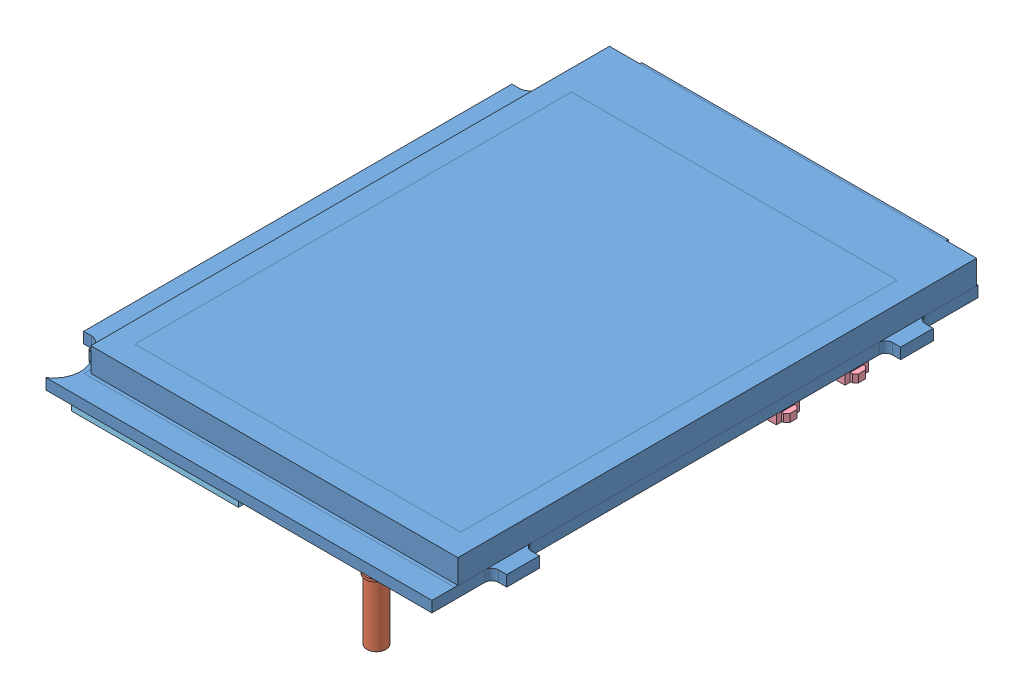
SolidWorks assembly Electronics21-08-2015, configuration Default. Lengths in mm.
Overall size (63.25 16.29 82.33).
8 component instances, 7 part files, 14 mates.
Components (placement in the parent):
- display21-08-2015-1: display21-08-2015 [Default] at (-1 0.5751 0) size (63.25 7.23 81.89)
- BIVAR LIGHTPIPE PLP2-12521-08-2015-1: BIVAR LIGHTPIPE PLP2-12521-08-2015 [Default] at (15.3149 -7.9169 38.0247) x (0.952304 0 -0.305152) z (0 1 0) size (3.35 3.46 9.96)
- micro-usb21-08-2015-1: micro-usb21-08-2015 [Default] at (-0.6 -5.7049 6) x (0 0 -1) z (0 -1 0) size (7.98 2.76 5.43)
- b3u-3100p-b21-08-2015-1: b3u-3100p-b21-08-2015 [Default] at (25.0639 -2.9504 -22.73) x (0 0 1) z (1 0 0) size (4.67 1.98 4.49)
- b3u-3100p-b21-08-2015-2: b3u-3100p-b21-08-2015 [Default] at (25.0639 -2.9504 -12.4419) x (0 0 1) z (1 0 0) size (4.67 1.98 4.49)
- Copy of Copy of Wifi-chip^Electronics21-08-2015-1: Copy of Copy of Wifi-chip^Electronics21-08-2015 [Default] at (-2.5 -2.8549 5.8984) x (0 0 1) z (1 0 0) size (35 2.3 25) (virtual)
- 3 COLOR LED21-08-2015-1: 3 COLOR LED21-08-2015 [Default] at (15.2723 -2.8549 38.0029) x (0 0 1) z (0 -1 0) size (3.2 2.6 1.1)
- Battery-holder21-08-2015-1: Battery-holder21-08-2015 [Default] at (0 -1.3481 2) size (46.5 5.9 41.87)
Mates (geometry in assembly coordinates):
- Coincident56: coincident anti-aligned: plane of display21-08-2015-1 through (-1 -2.8549 0) normal (0 -1 0); plane of micro-usb21-08-2015-1 through (2.4852 -2.8549 0.2454) normal (0 1 0)
- Coincident53: coincident anti-aligned: plane of display21-08-2015-1 through (-1 -2.8549 0) normal (0 -1 0); plane of b3u-3100p-b21-08-2015-1 through (23.5833 -2.8549 -22.73) normal (0 1 0)
- Distance22: distance = 0 mm aligned: plane of b3u-3100p-b21-08-2015-1 through (26.5 -3.5549 -22.73) normal (1 0 0); plane of display21-08-2015-1 through (26.5 -2.8549 40.8984) normal (1 0 0)
- Coincident54: coincident anti-aligned: plane of display21-08-2015-1 through (-1 -2.8549 0) normal (0 -1 0); plane of b3u-3100p-b21-08-2015-2 through (23.5833 -2.8549 -12.4419) normal (0 1 0)
- Coincident59: coincident aligned: plane of b3u-3100p-b21-08-2015-1 through (26.5 -3.5549 -22.73) normal (1 0 0); plane of b3u-3100p-b21-08-2015-2 through (26.5 -3.5549 -12.4419) normal (1 0 0)
- Coincident57: coincident anti-aligned: plane of display21-08-2015-1 through (-1 -2.8549 0) normal (0 -1 0); plane of Copy of Copy of Wifi-chip^Electronics21-08-2015-1 through (-2.5 -2.8549 5.8984) normal (0 1 0)
- Distance27: distance = 7 mm aligned: plane of Copy of Copy of Wifi-chip^Electronics21-08-2015-1 through (-27.5 -3.6549 5.8984) normal (-1 0 0); plane of display21-08-2015-1 through (-34.5 -2.8549 40.8984) normal (-1 0 0)
- Coincident49: coincident anti-aligned: plane of display21-08-2015-1 through (-1 -2.8549 0) normal (0 -1 0); plane of 3 COLOR LED21-08-2015-1 through (15.2723 -2.8549 38.0029) normal (0 1 0)
- Tangent8: tangent: plane of 3 COLOR LED21-08-2015-1 through (15.2723 -3.9549 38.0029) normal (0 -1 0); face of BIVAR LIGHTPIPE PLP2-12521-08-2015-1
- Coincident60: coincident aligned: plane of display21-08-2015-1 through (-34.5 -2.8549 40.8984) normal (0 0 1); plane of Copy of Copy of Wifi-chip^Electronics21-08-2015-1 through (-2.5 -3.6549 40.8984) normal (0 0 1)
- Distance30: distance = 0.6 mm aligned: plane of micro-usb21-08-2015-1; plane of assembly through (0 0 0) normal (1 0 0)
- Distance31: distance = 6 mm anti-aligned: plane of micro-usb21-08-2015-1; plane of assembly through (0 0 0) normal (0 0 1)
- Coincident61: coincident aligned: plane of Battery-holder21-08-2015-1 through (0 -1.3481 2) normal (1 0 0); plane of assembly through (0 0 0) normal (1 0 0)
- Distance32: distance = 1 mm aligned: plane of display21-08-2015-1 through (-1 0.5751 0) normal (1 0 0); plane of assembly through (0 0 0) normal (1 0 0)
